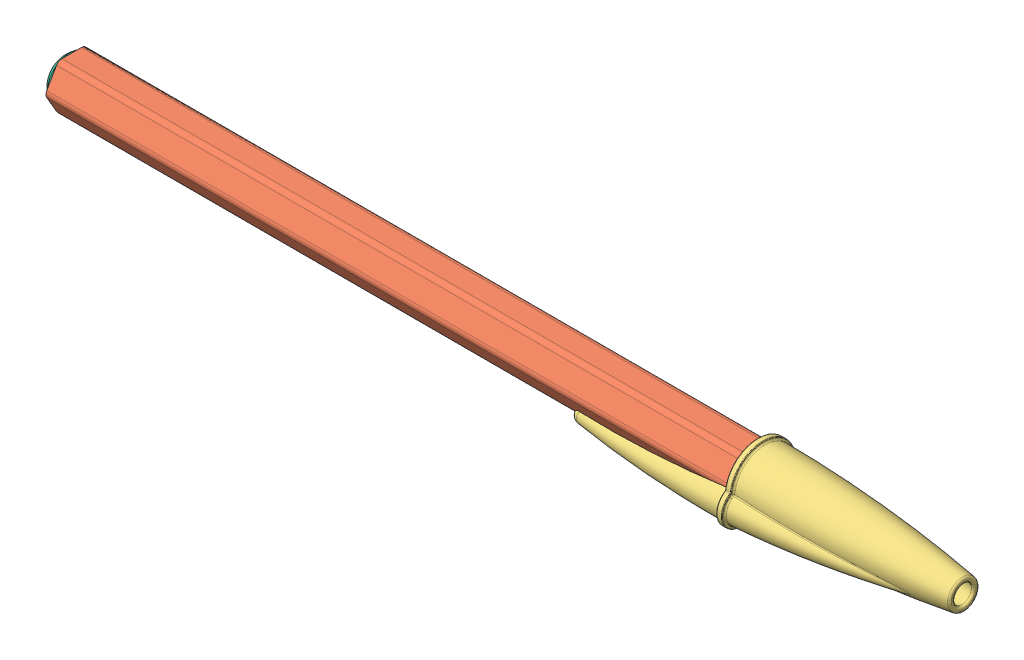
SolidWorks assembly BIC Pen Assembly Blue, configuration Default. Lengths in mm.
Overall size (148.8 15.39 16.22).
7 component instances, 7 part files, 0 mates.
Components (placement in the parent):
- Nib-1: Nib [Default] at (57.1345 -8.7544 -20.0258) x (1 0 0) z (0 0.001361 0.999999) size (15.6 3.6 3.6)
- Body-1: Body [Default] at (49.2214 -8.7544 -20.0258) size (134 7.6 8.57)
- Pen Cap (Blue)-1: Pen Cap (Blue) [Default] at (28.2214 -8.7544 -20.0258) x (-1 0 0) z (0 0.890697 0.454597) size (60 12.7 10.8)
- Nib Shroud-1: Nib Shroud [Default] at (54.7214 -8.7544 -20.0258) x (1 0 0) z (0 -0.048991 0.998799) size (14.5 5.4 5.4)
- Nib Roller Ball-1: Nib Roller Ball [Default] at (57.1345 -8.7544 -20.0258) size (1.59 1.59 1.59)
- End Cap (Blue)-1: End Cap (Blue) [Default] at (-79.2786 -8.7544 -20.0258) size (7.3 7.4 7.4)
- Ink Tube-Vessel (Blue)-1: Ink Tube-Vessel (Blue) [Default] at (48.0214 -8.7544 -20.0258) size (120 2.96 2.96)
